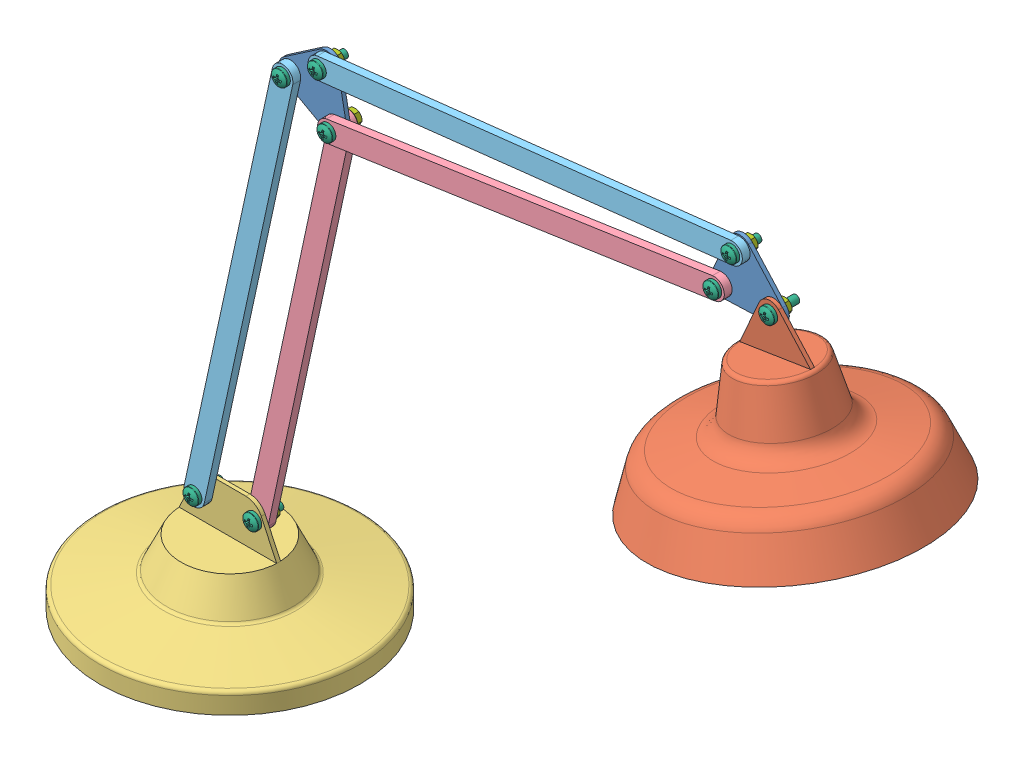
SolidWorks assembly bureaulamp 2.0, configuration Default. Lengths in mm.
Overall size (636.54 448.15 203).
24 component instances, 7 part files, 57 mates.
Components (placement in the parent):
- driehoek bureaulamp-2: driehoek bureaulamp [Default] at (57.0447 377.6895 -1.5) x (0.8748 -0.484484 0) z (0 0 1) size (58 48 3)
- lampenkap-1: lampenkap [Default] at (437.7815 295.2813 3) x (0 0 -1) z (0.98761 0.15693 0) size (200 123.98 200)
- lampstandaart-1: lampstandaart [Default] at origin size (200 83 200)
- staafje 320 en 300-1: staafje 320 en 300 [staafje 300] at (90.8348 361.6272 -7.5) x (0.977692 -0.210044 0) z (0 0 1) size (16 316 6)
- staafje 320 2.0-1: staafje 320 2.0 [Default] at (55.8384 380.9864 1.5) x (0.977147 -0.212566 0) z (0 0 1) size (16 336 6)
- staafje 320 2.0-2: staafje 320 2.0 [Default] at (394.528 429.9215 1.5) x (0.113145 -0.993578 0) z (0 0 1) size (16 336 6)
- staafje 320 en 300-2: staafje 320 en 300 [staafje 300] at (380.9402 399.4116 1.5) x (0.146725 -0.989177 0) z (0 0 1) size (16 316 6)
- driehoek bureaulamp-5: driehoek bureaulamp [Default] at (390.074 407.7146 -1.5) x (0.999287 0.037763 0) z (0 0 1) size (58 48 3)
- pan head cross recess screw_iso-18: pan head cross recess screw_iso [ISO 7045 - M6 x 20 - Z - 20N] at (379.7664 407.3251 12.1) x (0 0 -1) z (0.995933 -0.090097 0) size (24.48 12 12)
- pan head cross recess screw_iso-19: pan head cross recess screw_iso [ISO 7045 - M6 x 20 - Z - 20N] at (419.7379 408.8356 9.1) x (0 0 -1) z (0.995933 -0.090097 0) size (24.48 12 12)
- pan head cross recess screw_iso-20: pan head cross recess screw_iso [ISO 7045 - M6 x 20 - Z - 20N] at (393.6228 437.8701 12.1) x (0 0 -1) z (0.995933 -0.090097 0) size (24.48 12 12)
- pan head cross recess screw_iso-21: pan head cross recess screw_iso [ISO 7045 - M6 x 20 - Z - 20N] at (75.6777 401.6637 12.1) x (0 0 -1) z (0.995933 -0.090097 0) size (24.48 12 12)
- pan head cross recess screw_iso-22: pan head cross recess screw_iso [ISO 7045 - M6 x 20 - Z - 20N] at (48.0212 382.6869 12.1) x (0 0 -1) z (0.995933 -0.090097 0) size (24.48 12 12)
- pan head cross recess screw_iso-24: pan head cross recess screw_iso [ISO 7045 - M6 x 20 - Z - 20N] at (-20 70 12.1) x (0 0 -1) z (0.995933 -0.090097 0) size (24.48 12 12)
- pan head cross recess screw_iso-25: pan head cross recess screw_iso [ISO 7045 - M6 x 20 - Z - 20N] at (20 70 6.1) x (0 0 -1) z (0.995933 -0.090097 0) size (24.48 12 12)
- hex flange nut gradea_iso-2: hex flange nut gradea_iso [ISO - 4161 - M6 - N] at (20 70 -13.5) x (-0.829071 0.559143 0) z (0 0 -1) size (14.2 14.2 6)
- hex flange nut gradea_iso-3: hex flange nut gradea_iso [ISO - 4161 - M6 - N] at (-20 70 -7.5) x (-0.829071 0.559143 0) z (0 0 -1) size (14.2 14.2 6)
- hex flange nut gradea_iso-4: hex flange nut gradea_iso [ISO - 4161 - M6 - N] at (75.6777 401.6637 -7.5) x (-0.829071 0.559143 0) z (0 0 -1) size (14.2 14.2 6)
- hex flange nut gradea_iso-5: hex flange nut gradea_iso [ISO - 4161 - M6 - N] at (48.0212 382.6869 -7.5) x (-0.829071 0.559143 0) z (0 0 -1) size (14.2 14.2 6)
- hex flange nut gradea_iso-6: hex flange nut gradea_iso [ISO - 4161 - M6 - N] at (83.0132 363.3076 -13.5) x (-0.829071 0.559143 0) z (0 0 -1) size (14.2 14.2 6)
- hex flange nut gradea_iso-7: hex flange nut gradea_iso [ISO - 4161 - M6 - N] at (379.7664 407.3251 -7.5) x (-0.829071 0.559143 0) z (0 0 -1) size (14.2 14.2 6)
- hex flange nut gradea_iso-8: hex flange nut gradea_iso [ISO - 4161 - M6 - N] at (419.7379 408.8356 -7.5) x (-0.829071 0.559143 0) z (0 0 -1) size (14.2 14.2 6)
- hex flange nut gradea_iso-9: hex flange nut gradea_iso [ISO - 4161 - M6 - N] at (393.6228 437.8701 -7.5) x (-0.829071 0.559143 0) z (0 0 -1) size (14.2 14.2 6)
- pan head cross recess screw_iso-26: pan head cross recess screw_iso [ISO 7045 - M6 x 20 - Z - 20N] at (83.0132 363.3076 12.1) x (0 0 -1) z (0.995933 -0.090097 0) size (24.48 12 12)
Mates (geometry in assembly coordinates):
- Coincident2: coincident anti-aligned: plane of lampstandaart-1 through (13.8299 70 -1.5) normal (0 0 -1); circle of staafje 320 en 300-1
- Concentric3: concentric aligned: circle of lampstandaart-1; circle of staafje 320 2.0-1
- Coincident3: coincident anti-aligned: plane of driehoek bureaulamp-2 through (48.0212 382.6869 -1.5) normal (0 0 -1); plane of staafje 320 en 300-1 through (83.0132 363.3076 -1.5) normal (0 0 1)
- Concentric1: concentric aligned: circle of driehoek bureaulamp-2; circle of staafje 320 2.0-1
- Concentric2: concentric aligned: cylinder of driehoek bureaulamp-2 through (83.0132 363.3076 1.5) axis (0 0 -1) radius 3; cylinder of staafje 320 en 300-1 through (83.0132 363.3076 -1.5) axis (0 0 -1) radius 3.25
- Concentric4: concentric aligned: cylinder of lampstandaart-1 through (20 70 1.5) axis (0 0 -1) radius 3; cylinder of staafje 320 en 300-1 through (20 70 -1.5) axis (0 0 -1) radius 3.25
- Concentric7: concentric aligned: cylinder of driehoek bureaulamp-2 through (83.0132 363.3076 1.5) axis (0 0 -1) radius 3; cylinder of staafje 320 en 300-2 through (83.0132 363.3076 7.5) axis (0 0 -1) radius 3.25
- Coincident10: coincident anti-aligned: plane of driehoek bureaulamp-2 through (48.0212 382.6869 1.5) normal (0 0 1); plane of staafje 320 en 300-2 through (379.7664 407.3251 1.5) normal (0 0 -1)
- Coincident11: coincident anti-aligned: plane of driehoek bureaulamp-2 through (48.0212 382.6869 1.5) normal (0 0 1); plane of staafje 320 2.0-2 through (393.6228 437.8701 1.5) normal (0 0 -1)
- Concentric14: concentric aligned: cylinder of driehoek bureaulamp-2 through (75.6777 401.6637 1.5) axis (0 0 -1) radius 3; cylinder of staafje 320 2.0-2 through (75.6777 401.6637 7.5) axis (0 0 -1) radius 3.25
- Concentric15: concentric aligned: cylinder of lampstandaart-1 through (-20 70 1.5) axis (0 0 -1) radius 3; cylinder of staafje 320 2.0-1 through (-20 70 7.5) axis (0 0 -1) radius 3.25
- Coincident12: coincident anti-aligned: plane of lampstandaart-1 through (13.8299 70 1.5) normal (0 0 1); plane of staafje 320 2.0-1 through (48.0212 382.6869 1.5) normal (0 0 -1)
- Coincident13: coincident anti-aligned: plane of staafje 320 en 300-2 through (379.7664 407.3251 1.5) normal (0 0 -1); plane of driehoek bureaulamp-5 through (379.7664 407.3251 1.5) normal (0 0 1)
- Concentric16: concentric aligned: cylinder of staafje 320 en 300-2 through (379.7664 407.3251 7.5) axis (0 0 -1) radius 3.25; cylinder of driehoek bureaulamp-5 through (379.7664 407.3251 1.5) axis (0 0 -1) radius 3
- Concentric17: concentric aligned: cylinder of staafje 320 2.0-2 through (393.6228 437.8701 7.5) axis (0 0 -1) radius 3.25; cylinder of driehoek bureaulamp-5 through (393.6228 437.8701 1.5) axis (0 0 -1) radius 3
- Concentric18: concentric anti-aligned: cylinder of lampenkap-1 through (419.7379 408.8356 1.5) axis (0 0 1) radius 3; cylinder of driehoek bureaulamp-5 through (419.7379 408.8356 1.5) axis (0 0 -1) radius 3
- Coincident14: coincident anti-aligned: plane of lampenkap-1 through (419.7379 408.8356 1.5) normal (0 0 -1); plane of driehoek bureaulamp-5 through (379.7664 407.3251 1.5) normal (0 0 1)
- Concentric31: concentric anti-aligned: cylinder of staafje 320 en 300-2 through (379.7664 407.3251 7.5) axis (0 0 -1) radius 3.25; cylinder of pan head cross recess screw_iso-18 through (379.7664 407.3251 37.5) axis (0 0 1) radius 6
- Coincident29: coincident anti-aligned: plane of staafje 320 en 300-2 through (379.7664 407.3251 7.5) normal (0 0 1); plane of pan head cross recess screw_iso-18 through (380.0367 410.3129 7.5) normal (0 0 -1)
- Concentric32: concentric aligned: cylinder of lampenkap-1 through (419.7379 408.8356 1.5) axis (0 0 1) radius 3; cylinder of pan head cross recess screw_iso-19 through (419.7379 408.8356 34.5) axis (0 0 1) radius 6
- Coincident30: coincident anti-aligned: plane of lampenkap-1 through (419.7379 408.8356 4.5) normal (0 0 1); plane of pan head cross recess screw_iso-19 through (420.0082 411.8234 4.5) normal (0 0 -1)
- Concentric33: concentric anti-aligned: cylinder of staafje 320 2.0-2 through (393.6228 437.8701 7.5) axis (0 0 -1) radius 3.25; cylinder of pan head cross recess screw_iso-20 through (393.6228 437.8701 37.5) axis (0 0 1) radius 6
- Coincident31: coincident anti-aligned: plane of staafje 320 2.0-2 through (393.6228 437.8701 7.5) normal (0 0 1); plane of pan head cross recess screw_iso-20 through (393.8931 440.8579 7.5) normal (0 0 -1)
- Concentric34: concentric anti-aligned: cylinder of staafje 320 2.0-2 through (75.6777 401.6637 7.5) axis (0 0 -1) radius 8; cylinder of pan head cross recess screw_iso-21 through (75.6777 401.6637 37.5) axis (0 0 1) radius 6
- Coincident32: coincident anti-aligned: plane of staafje 320 2.0-2 through (393.6228 437.8701 7.5) normal (0 0 1); plane of pan head cross recess screw_iso-21 through (75.948 404.6515 7.5) normal (0 0 -1)
- Concentric35: concentric anti-aligned: cylinder of staafje 320 2.0-1 through (48.0212 382.6869 7.5) axis (0 0 -1) radius 3.25; cylinder of pan head cross recess screw_iso-22 through (48.0212 382.6869 37.5) axis (0 0 1) radius 6
- Coincident33: coincident anti-aligned: plane of staafje 320 2.0-1 through (48.0212 382.6869 7.5) normal (0 0 1); plane of pan head cross recess screw_iso-22 through (48.2915 385.6747 7.5) normal (0 0 -1)
- Concentric37: concentric anti-aligned: cylinder of staafje 320 2.0-1 through (-20 70 7.5) axis (0 0 -1) radius 3.25; cylinder of pan head cross recess screw_iso-24 through (-20 70 37.5) axis (0 0 1) radius 6
- Coincident35: coincident anti-aligned: plane of staafje 320 2.0-1 through (48.0212 382.6869 7.5) normal (0 0 1); plane of pan head cross recess screw_iso-24 through (-19.7297 72.9878 7.5) normal (0 0 -1)
- Concentric38: concentric anti-aligned: cylinder of lampstandaart-1 through (20 70 1.5) axis (0 0 -1) radius 3; cylinder of pan head cross recess screw_iso-25 through (20 70 31.5) axis (0 0 1) radius 6
- Coincident36: coincident anti-aligned: plane of lampstandaart-1 through (13.8299 70 1.5) normal (0 0 1); plane of pan head cross recess screw_iso-25 through (20.2703 72.9878 1.5) normal (0 0 -1)
- Concentric39: concentric aligned: cylinder of staafje 320 en 300-1 through (20 70 -1.5) axis (0 0 -1) radius 3.25; cylinder of hex flange nut gradea_iso-2 through (20 70 11.5375) axis (0 0 -1) radius 3
- Coincident37: coincident anti-aligned: plane of staafje 320 en 300-1 through (83.0132 363.3076 -7.5) normal (0 0 -1); plane of hex flange nut gradea_iso-2 through (23.2282 74.7866 -7.5) normal (0 0 1)
- Concentric40: concentric aligned: cylinder of lampstandaart-1 through (-20 70 1.5) axis (0 0 -1) radius 3; cylinder of hex flange nut gradea_iso-3 through (-20 70 17.5375) axis (0 0 -1) radius 3
- Coincident38: coincident anti-aligned: plane of lampstandaart-1 through (13.8299 70 -1.5) normal (0 0 -1); plane of hex flange nut gradea_iso-3 through (-16.7718 74.7866 -1.5) normal (0 0 1)
- Concentric41: concentric aligned: cylinder of driehoek bureaulamp-2 through (75.6777 401.6637 1.5) axis (0 0 -1) radius 3; cylinder of hex flange nut gradea_iso-4 through (75.6777 401.6637 17.5375) axis (0 0 -1) radius 3
- Coincident39: coincident anti-aligned: plane of driehoek bureaulamp-2 through (48.0212 382.6869 -1.5) normal (0 0 -1); plane of hex flange nut gradea_iso-4 through (78.9059 406.4503 -1.5) normal (0 0 1)
- Concentric42: concentric aligned: cylinder of driehoek bureaulamp-2 through (48.0212 382.6869 1.5) axis (0 0 -1) radius 9; cylinder of hex flange nut gradea_iso-5 through (48.0212 382.6869 17.5375) axis (0 0 -1) radius 3
- Coincident40: coincident anti-aligned: plane of driehoek bureaulamp-2 through (48.0212 382.6869 -1.5) normal (0 0 -1); plane of hex flange nut gradea_iso-5 through (51.2494 387.4736 -1.5) normal (0 0 1)
- Concentric43: concentric aligned: cylinder of staafje 320 en 300-1 through (83.0132 363.3076 -1.5) axis (0 0 -1) radius 3.25; cylinder of hex flange nut gradea_iso-6 through (83.0132 363.3076 11.5375) axis (0 0 -1) radius 3
- Coincident41: coincident anti-aligned: plane of staafje 320 en 300-1 through (83.0132 363.3076 -7.5) normal (0 0 -1); plane of hex flange nut gradea_iso-6 through (86.2414 368.0942 -7.5) normal (0 0 1)
- Concentric44: concentric aligned: cylinder of driehoek bureaulamp-5 through (379.7664 407.3251 1.5) axis (0 0 -1) radius 9; cylinder of hex flange nut gradea_iso-7 through (379.7664 407.3251 17.5375) axis (0 0 -1) radius 3
- Coincident42: coincident anti-aligned: plane of driehoek bureaulamp-5 through (379.7664 407.3251 -1.5) normal (0 0 -1); plane of hex flange nut gradea_iso-7 through (382.9946 412.1117 -1.5) normal (0 0 1)
- Concentric45: concentric aligned: cylinder of driehoek bureaulamp-5 through (419.7379 408.8356 1.5) axis (0 0 -1) radius 3; cylinder of hex flange nut gradea_iso-8 through (419.7379 408.8356 17.5375) axis (0 0 -1) radius 3
- Coincident43: coincident anti-aligned: plane of driehoek bureaulamp-5 through (379.7664 407.3251 -1.5) normal (0 0 -1); plane of hex flange nut gradea_iso-8 through (422.9661 413.6222 -1.5) normal (0 0 1)
- Concentric46: concentric aligned: cylinder of driehoek bureaulamp-5 through (393.6228 437.8701 1.5) axis (0 0 -1) radius 3; cylinder of hex flange nut gradea_iso-9 through (393.6228 437.8701 17.5375) axis (0 0 -1) radius 3
- Coincident44: coincident anti-aligned: plane of driehoek bureaulamp-5 through (379.7664 407.3251 -1.5) normal (0 0 -1); plane of hex flange nut gradea_iso-9 through (396.8511 442.6567 -1.5) normal (0 0 1)
- Concentric47: concentric anti-aligned: cylinder of staafje 320 en 300-2 through (83.0132 363.3076 7.5) axis (0 0 -1) radius 3.25; cylinder of pan head cross recess screw_iso-26 through (83.0132 363.3076 37.5) axis (0 0 1) radius 6
- Coincident45: coincident anti-aligned: plane of staafje 320 en 300-2 through (379.7664 407.3251 7.5) normal (0 0 1); plane of pan head cross recess screw_iso-26 through (83.2835 366.2954 7.5) normal (0 0 -1)
- Coincident46: coincident aligned: plane of lampstandaart-1 through (0 0 0) normal (0 0 1); plane of assembly through (0 0 0) normal (0 0 1)
- Coincident47: coincident aligned: plane of lampstandaart-1 through (0 0 0) normal (0 1 0); plane of assembly through (0 0 0) normal (0 1 0)
- Coincident48: coincident aligned: plane of lampstandaart-1 through (0 0 0) normal (1 0 0); plane of assembly through (0 0 0) normal (1 0 0)
- LimitDistance1: limit distance = 12.186 mm: line of staafje 320 2.0-2 through (394.528 429.9215 7.5) axis (0 0 -1); plane of staafje 320 en 300-2 through (81.8394 371.221 7.5) normal (-0.146725 0.989177 0)
- LimitDistance3: limit distance = 22.3117 mm: plane of staafje 320 2.0-1 through (55.8384 380.9864 7.5) normal (0.977147 -0.212566 0); line of staafje 320 en 300-1 through (75.1917 364.9879 -1.5) axis (0 0 -1)
- LimitDistance4: limit distance = 22.9444 mm: plane of staafje 320 2.0-2 through (394.528 429.9215 7.5) normal (0.113145 -0.993578 0); line of staafje 320 en 300-2 through (81.8394 371.221 7.5) axis (0 0 -1)
- LimitDistance5: limit distance = 23.1077 mm: line of staafje 320 2.0-1 through (-12.1828 68.2995 7.5) axis (0 0 -1); plane of staafje 320 en 300-1 through (12.1785 71.6804 -1.5) normal (-0.977692 0.210044 0)
- Angle4: planar angle = 3.141593 rad anti-aligned: plane of lampenkap-1 through (426.4294 414.8542 1.5) normal (0.743498 0.668738 0); plane of driehoek bureaulamp-5 through (400.3143 443.8887 1.5) normal (0.743498 0.668738 0)
